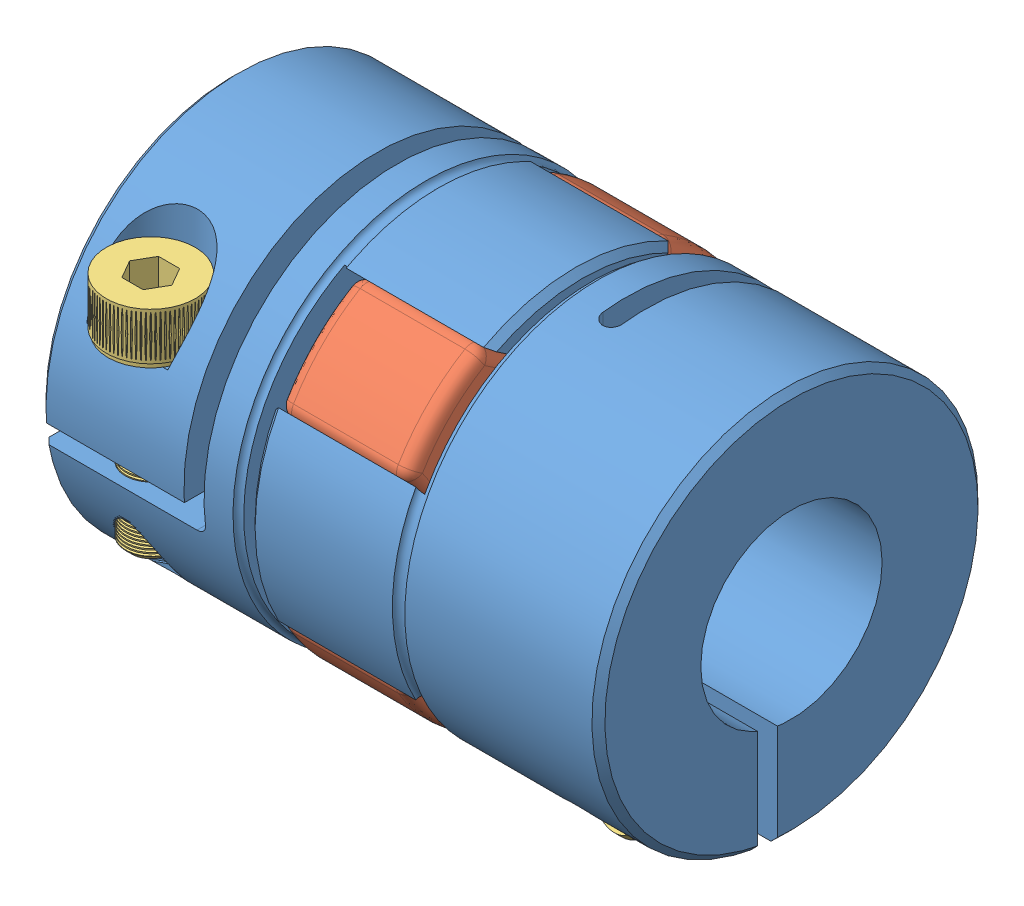
SolidWorks assembly Chinese Shaft Coupling, configuration Default. Lengths in mm.
Overall size (42.98 31.13 30.08).
5 component instances, 3 part files, 12 mates.
Components (placement in the parent):
- Shaft Coupling - Acoplamiento Lineal-1: Shaft Coupling - Acoplamiento Lineal [Default] at (1.3369 9.1292 -6.9077) size (26.9 29.7 29.7)
- Shaft Coupling - Acoplamiento Lineal-2: Shaft Coupling - Acoplamiento Lineal [Default] at (12.1569 9.1292 -6.9077) x (-1 0 0) z (0 -1 0) size (26.9 29.7 29.7)
- PRU Spider-1: PRU Spider [Default] at (11.7469 9.1292 -6.9077) x (-1 0 0) z (0 0 1) size (12.26 25.78 25.78)
- Allen Screw - Tornillo Allen-1: Allen Screw - Tornillo Allen [Default] at (22.7169 -2.6815 -16.8277) x (-0.923728 -0.383049 0) z (0 0 -1) size (6.84 6.84 18)
- Allen Screw - Tornillo Allen-2: Allen Screw - Tornillo Allen [Default] at (-9.2231 19.0492 4.903) x (1 0 0) z (0 1 0) size (6.84 6.84 18)
Mates (geometry in assembly coordinates):
- Coincidente1: coincident anti-aligned: plane of Shaft Coupling - Acoplamiento Lineal-1 through (12.8769 23.6292 -6.9077) normal (-1 0 0); plane of PRU Spider-1 through (12.8769 2.4294 -13.6076) normal (1 0 0)
- Coincidente4: coincident anti-aligned: plane of Shaft Coupling - Acoplamiento Lineal-2 through (0.6169 9.1292 -21.4077) normal (1 0 0); plane of PRU Spider-1 through (0.6169 2.4294 -13.6076) normal (-1 0 0)
- Coincidente7: coincident anti-aligned: plane of Shaft Coupling - Acoplamiento Lineal-1 through (24.6719 -2.6815 -12.8277) normal (0 0 -1); plane of Allen Screw - Tornillo Allen-1 through (21.4597 0.3502 -12.8277) normal (0 0 1)
- Concéntrica1: concentric aligned: circle of Shaft Coupling - Acoplamiento Lineal-1; circle of Allen Screw - Tornillo Allen-1
- Coincidente8: coincident anti-aligned: plane of Shaft Coupling - Acoplamiento Lineal-2 through (-11.1781 15.0492 4.903) normal (0 1 0); plane of Allen Screw - Tornillo Allen-2 through (-9.2231 15.0492 1.6209) normal (0 -1 0)
- Concéntrica2: concentric anti-aligned: circle of Shaft Coupling - Acoplamiento Lineal-2; circle of Allen Screw - Tornillo Allen-2
- Coincidente11: coincident anti-aligned: plane of Shaft Coupling - Acoplamiento Lineal-1 through (12.8769 23.6292 -6.9077) normal (-1 0 0); plane of PRU Spider-1 through (12.8769 2.4294 -13.6076) normal (1 0 0)
- Coincidente14: coincident anti-aligned: plane of Shaft Coupling - Acoplamiento Lineal-2 through (0.6169 9.1292 -21.4077) normal (1 0 0); plane of PRU Spider-1 through (0.6169 2.4294 -13.6076) normal (-1 0 0)
- Concéntrica3: concentric anti-aligned: cylinder of Shaft Coupling - Acoplamiento Lineal-1 through (12.8769 -5.3708 -6.9077) axis (-1 0 0) radius 15; cylinder of PRU Spider-1 through (1.6869 -5.3708 -6.9077) axis (1 0 0) radius 15
- Concéntrica4: concentric anti-aligned: cylinder of Shaft Coupling - Acoplamiento Lineal-1 through (12.8769 23.6292 -6.9077) axis (-1 0 0) radius 15; cylinder of PRU Spider-1 through (1.6869 23.6292 -6.9077) axis (1 0 0) radius 15
- Concéntrica5: concentric aligned: cylinder of Shaft Coupling - Acoplamiento Lineal-2 through (0.6169 9.1292 -21.4077) axis (1 0 0) radius 15; cylinder of PRU Spider-1 through (1.6869 9.1292 -21.4077) axis (1 0 0) radius 15
- Concéntrica6: concentric aligned: cylinder of Shaft Coupling - Acoplamiento Lineal-2 through (0.6169 9.1292 7.5923) axis (1 0 0) radius 15; cylinder of PRU Spider-1 through (1.6869 9.1292 7.5923) axis (1 0 0) radius 15
